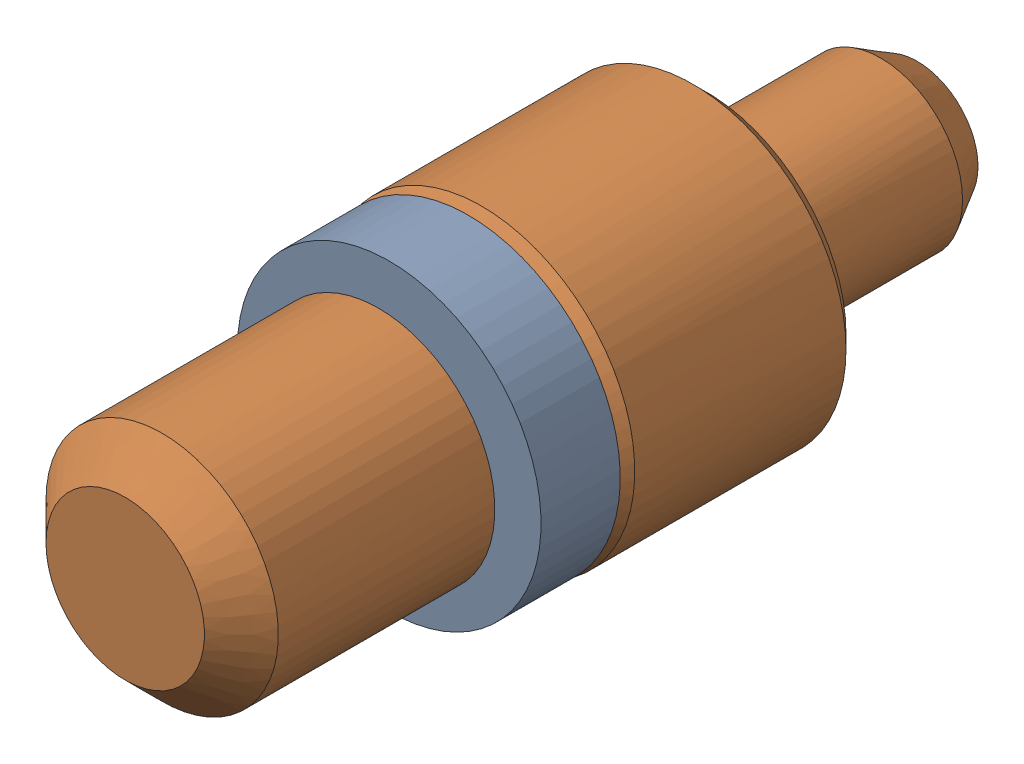
SolidWorks assembly Pogo Pin Asmbly_4, configuration Default. Lengths in mm.
Overall size (2.95 2.95 7.62).
2 component instances, 2 part files, 0 mates.
Components (placement in the parent):
- Pogo O-Ring-1: Pogo O-Ring [Default] at (70.9348 51.8601 -6.223) size (2.92 2.92 0.76)
- Pogo Contact Pin-1: Pogo Contact Pin [Default] at (70.9348 51.8601 -6.223) size (2.95 2.95 7.62)
